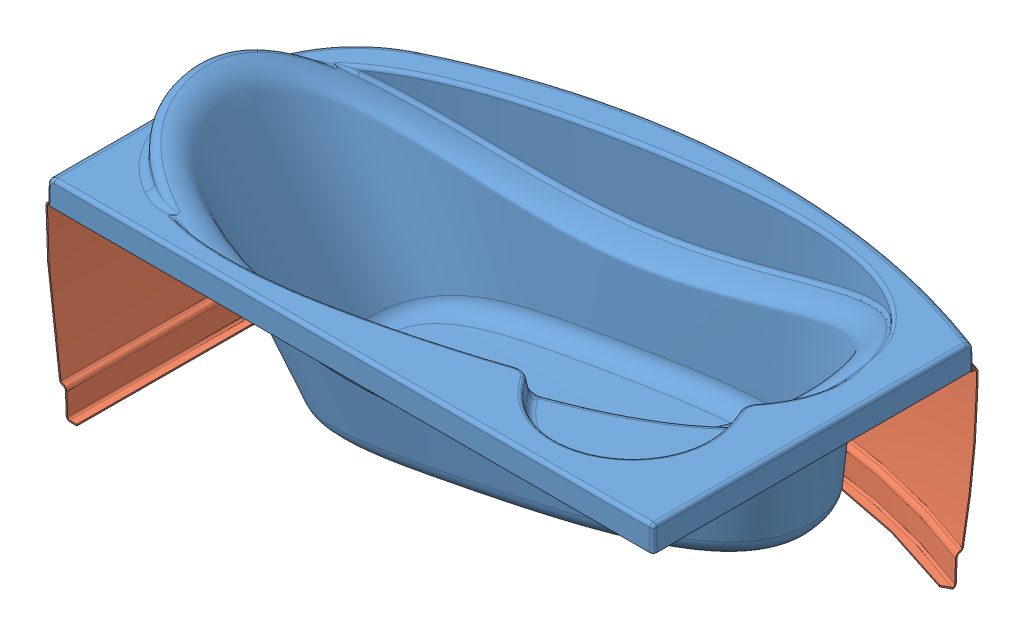
SolidWorks assembly Prestige 1709124L, configuration По умолчанию. Lengths in mm.
Overall size (1792.66 708.93 1118.58).
2 component instances, 2 part files, 2 mates.
Components (placement in the parent):
- Модель 1700x900(1020)L-1: Модель 1700x900(1020)L [По умолчанию] at origin size (1744.94 622.92 1118.58)
- панль угл3-1: панль угл3 [По умолчанию] at (-945.7866 0 842.6608) x (-0.999994 0 -0.003328) z (0.003328 0 -0.999994) size (1789.21 533.53 1041.12)
Mates (geometry in assembly coordinates):
- Совпадение6: coincident anti-aligned: plane of панль угл3-1 through (-945.2542 0 682.6626) normal (0 1 0); plane of Модель 1700x900(1020)L-1 through (108.7337 0 1566.5423) normal (0 -1 0)
- Концентричный1: concentric anti-aligned: circle of Модель 1700x900(1020)L-1; circle of панль угл3-1
